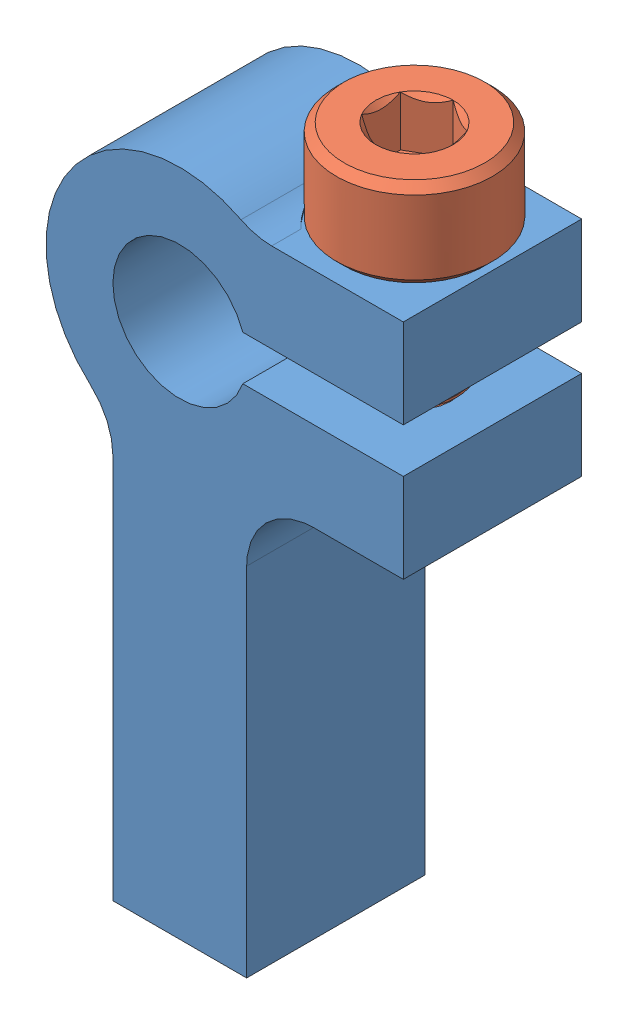
SolidWorks assembly 1-Side, 1-Post Clamping Mount (6mm Bore) 1403-0024-0006, configuration Default. Lengths in mm.
Overall size (16.03 33.01 8).
2 component instances, 2 part files, 0 mates.
Components (placement in the parent):
- 1403-0024-0006 without hardware.step-1: 1403-0024-0006 without hardware.step [Default] at (-14.5875 1.2633 -4.8945) size (16.03 30 8)
- 2800-0004-0010.step-1: 2800-0004-0010.step [Default] at (-8.0591 -3.7367 -0.8945) size (7 14.01 7)
